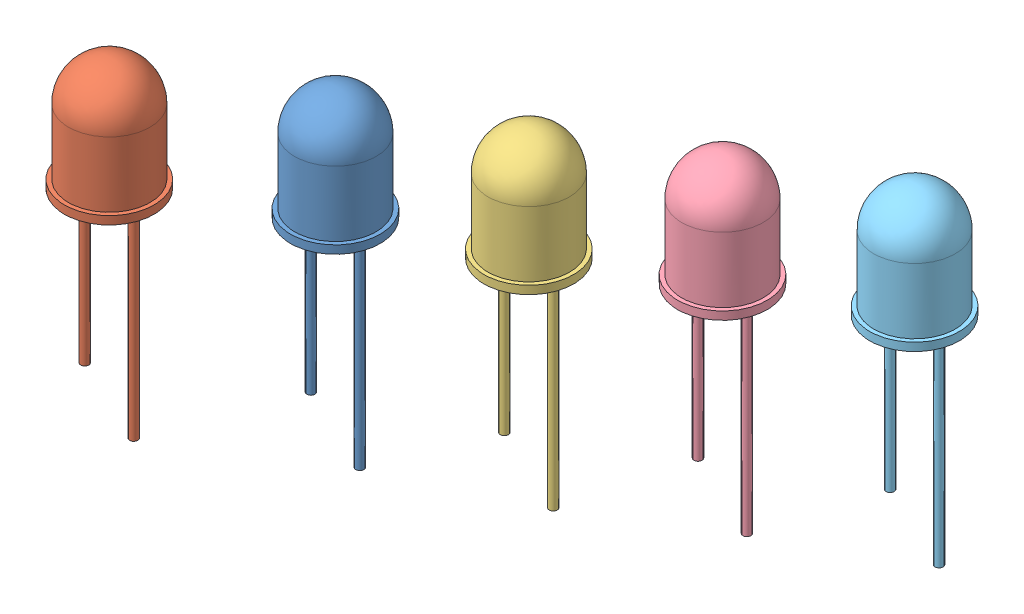
SolidWorks assembly Ledsall, configuration Default. Lengths in mm.
Overall size (77.14 44.86 43.61).
5 component instances, 5 part files, 0 mates.
Components (placement in the parent):
- Led grande Amarillo-1: Led grande Amarillo [Default] at (12.7743 24.8354 31.5678) size (11 39 11)
- Led grande Azul-1: Led grande Azul [Default] at (-1.6637 27.3655 44.8538) size (11 39 11)
- Led grande Rojo-1: Led grande Rojo [Default] at (30.2916 26.204 25.3647) size (11 39 11)
- Led grande transparente-1: Led grande transparente [Default] at (47.0393 28.3552 18.3707) size (11 39 11)
- Led grande verde-1: Led grande verde [Default] at (64.4739 30.6934 12.2479) size (11 39 11)
